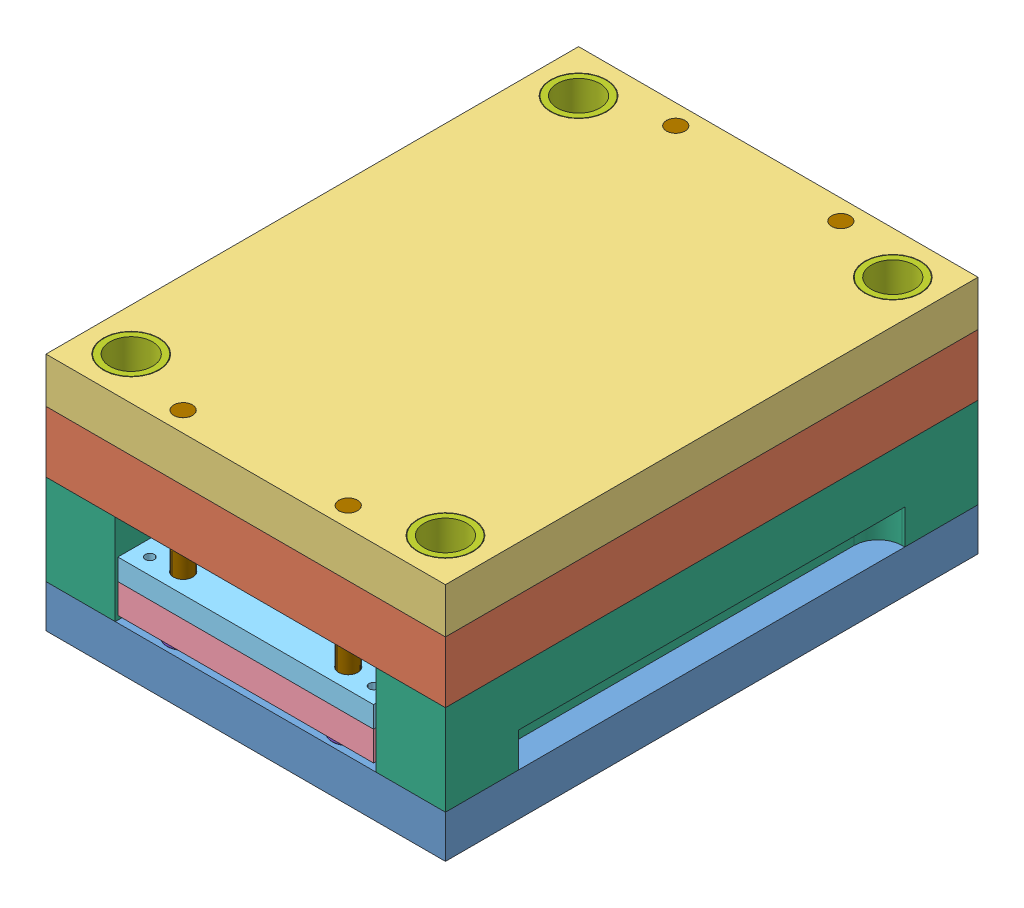
SolidWorks assembly Porta molde 300x400 Parte Inferior, configuration Valor predeterminado. Lengths in mm.
Overall size (300 180 401.07).
34 component instances, 12 part files, 38 mates.
Components (placement in the parent):
- Placa base inferior-1: Placa base inferior [Valor predeterminado] at (12.8367 -5.899 0) size (300 32 400)
- Placa suporte-1: Placa suporte [Valor predeterminado] at (12.8367 94.101 0) size (300 46 400)
- Placa cavidade P2-1: Placa cavidade P2 [Valor predeterminado] at (12.8367 140.101 0) size (300 34 400)
- Placa extratora CPE-1: Placa extratora CPE [Valor predeterminado] at (12.8367 53.101 0) x (-1 0 0) z (0 0 1) size (192 22 400)
- Placa extratora PE-1: Placa extratora PE [Valor predeterminado] at (12.8367 53.101 0) size (192 16 400)
- Espaçador-3: Espaçador [Valor predeterminado] at (110.8367 94.101 200) x (1 0 0) z (0 0 -1) size (52 68 400)
- Espaçador-4: Espaçador [Valor predeterminado] at (-85.1633 94.101 -200) x (-1 0 0) z (0 0 1) size (52 68 400)
- Socket Head Cap Screw_ISO-3: Socket Head Cap Screw_ISO [ISO 4762 M6 x 25 --- 25N] at (30.3367 349.101 -30.3109) x (0 -1 0) z (0.216767 0 0.976223) (suppressed, hidden)
- Socket Head Cap Screw_ISO-6: Socket Head Cap Screw_ISO [ISO 4762 M16 x 30 --- 30N] at (130.8367 340.101 -119) x (0 -1 0) z (0 0 1) (suppressed, hidden)
- Bucha-1: Bucha [B16] at (130.8367 140.101 168) x (0 1 0) z (0 0 1) size (34 48 48)
- Socket Head Cap Screw_ISO-10: Socket Head Cap Screw_ISO [ISO 4762 M16 x 150 --- 44N] at (130.8367 -5.899 -119) x (0 1 0) z (0 0 1) (suppressed, hidden)
- Bucha-2: Bucha [B16] at (130.8367 140.101 -168) x (0 1 0) z (0 0 1) size (34 48 48)
- Bucha-3: Bucha [B16] at (-105.1633 140.101 168) x (0 1 0) z (0 0 1) size (34 48 48)
- Bucha-4: Bucha [B16] at (-105.1633 140.101 -168) x (0 1 0) z (0 0 1) size (34 48 48)
- Socket Head Cap Screw_ISO-14: Socket Head Cap Screw_ISO [ISO 4762 M8 x 25 --- 25N] at (-71.1633 31.101 188) x (0 1 0) z (0 0 1) (suppressed, hidden)
- Socket Head Cap Screw_ISO-15: Socket Head Cap Screw_ISO [ISO 4762 M8 x 25 --- 25N] at (-71.1633 31.101 -188) x (0 1 0) z (0 0 1) (suppressed, hidden)
- Socket Head Cap Screw_ISO-16: Socket Head Cap Screw_ISO [ISO 4762 M8 x 25 --- 25N] at (96.8367 31.101 188) x (0 1 0) z (0 0 1) (suppressed, hidden)
- Socket Head Cap Screw_ISO-17: Socket Head Cap Screw_ISO [ISO 4762 M8 x 25 --- 25N] at (96.8367 31.101 -188) x (0 1 0) z (0 0 1) (suppressed, hidden)
- PA 02-1: PA 02 [Valor predeterminado] at (-49.1633 11.101 185) size (24 20 24)
- PA 02-2: PA 02 [Valor predeterminado] at (-49.1633 11.101 -185) size (24 20 24)
- PA 02-3: PA 02 [Valor predeterminado] at (74.8367 11.101 185) size (24 20 24)
- PA 02-4: PA 02 [Valor predeterminado] at (74.8367 11.101 -185) size (24 20 24)
- Extrator-1: Extrator [Valor predeterminado] at (-49.1633 53.101 185) x (0.670266 0 -0.742121) z (0.742121 0 0.670266) size (22 121 22)
- Extrator-2: Extrator [Valor predeterminado] at (-49.1633 53.101 -185) x (0.670266 0 -0.742121) z (0.742121 0 0.670266) size (22 121 22)
- Extrator-3: Extrator [Valor predeterminado] at (74.8367 53.101 185) x (0.670266 0 -0.742121) z (0.742121 0 0.670266) size (22 121 22)
- Extrator-4: Extrator [Valor predeterminado] at (74.8367 53.101 -185) x (0.670266 0 -0.742121) z (0.742121 0 0.670266) size (22 121 22)
- Bucha 2-1: Bucha 2 [Valor predeterminado] at (83.8367 31.101 153) x (0 1 0) z (0 0 1) size (38 38.1 38.1)
- Pino 2-1: Pino 2 [Valor predeterminado] at (83.8367 -5.899 153) x (0 1 0) z (0 0 1) size (102 38 38)
- Bucha 2-2: Bucha 2 [Valor predeterminado] at (83.8367 31.101 -153) x (0 1 0) z (0 0 1) size (38 38.1 38.1)
- Bucha 2-3: Bucha 2 [Valor predeterminado] at (-58.1633 31.101 153) x (0 1 0) z (0 0 1) size (38 38.1 38.1)
- Bucha 2-4: Bucha 2 [Valor predeterminado] at (-58.1633 31.101 -153) x (0 1 0) z (0 0 1) size (38 38.1 38.1)
- Pino 2-2: Pino 2 [Valor predeterminado] at (83.8367 -5.899 -153) x (0 1 0) z (0 0 1) size (102 38 38)
- Pino 2-3: Pino 2 [Valor predeterminado] at (-58.1633 -5.899 153) x (0 1 0) z (0 0 1) size (102 38 38)
- Pino 2-4: Pino 2 [Valor predeterminado] at (-58.1633 -5.899 -153) x (0 1 0) z (0 0 1) size (102 38 38)
Mates (geometry in assembly coordinates):
- Coincidente11: coincident anti-aligned: plane of Placa suporte-1 through (-137.1633 140.101 200) normal (0 1 0); plane of Placa cavidade P2-1 through (-137.1633 140.101 200) normal (0 -1 0)
- Coincidente12: coincident aligned: plane of Placa suporte-1 through (-137.1633 140.101 200) normal (0 0 1); plane of Placa cavidade P2-1 through (-137.1633 174.101 200) normal (0 0 1)
- Coincidente13: coincident aligned: plane of Placa suporte-1 through (162.8367 140.101 -200) normal (1 0 0); plane of Placa cavidade P2-1 through (162.8367 174.101 -200) normal (1 0 0)
- Paralelo1: parallel anti-aligned: plane of Placa base inferior-1 through (-137.1633 26.101 200) normal (0 1 0); plane of Placa extratora CPE-1 through (108.8367 31.101 200) normal (0 -1 0)
- Coincidente21: coincident aligned: plane of Placa base inferior-1 through (-137.1633 26.101 200) normal (0 0 1); plane of Placa extratora CPE-1 through (108.8367 31.101 200) normal (0 0 1)
- Coincidente22: coincident anti-aligned: plane of Placa extratora CPE-1 through (108.8367 53.101 200) normal (0 1 0); plane of Placa extratora PE-1 through (-83.1633 53.101 200) normal (0 -1 0)
- Coincidente23: coincident aligned: plane of Placa extratora CPE-1 through (108.8367 31.101 -200) normal (1 0 0); plane of Placa extratora PE-1 through (108.8367 69.101 -200) normal (1 0 0)
- Coincidente24: coincident aligned: plane of Placa extratora CPE-1 through (108.8367 31.101 200) normal (0 0 1); plane of Placa extratora PE-1 through (-83.1633 69.101 200) normal (0 0 1)
- Coincidente28: coincident anti-aligned: plane of Placa base inferior-1 through (-137.1633 26.101 200) normal (0 1 0); plane of Espaçador-3 through (110.8367 26.101 -200) normal (0 -1 0)
- Coincidente29: coincident aligned: plane of Placa base inferior-1 through (-137.1633 26.101 200) normal (0 0 1); plane of Espaçador-3 through (110.8367 26.101 200) normal (0 0 1)
- Coincidente30: coincident aligned: plane of Placa base inferior-1 through (162.8367 26.101 -200) normal (1 0 0); plane of Espaçador-3 through (162.8367 94.101 -200) normal (1 0 0)
- Coincidente31: coincident anti-aligned: plane of Placa suporte-1 through (-137.1633 94.101 200) normal (0 -1 0); plane of Espaçador-3 through (110.8367 94.101 -200) normal (0 1 0)
- Coincidente32: coincident aligned: plane of Placa suporte-1 through (162.8367 140.101 -200) normal (1 0 0); plane of Espaçador-3 through (162.8367 94.101 -200) normal (1 0 0)
- Coincidente33: coincident aligned: plane of Placa suporte-1 through (-137.1633 140.101 200) normal (0 0 1); plane of Espaçador-3 through (110.8367 26.101 200) normal (0 0 1)
- Coincidente34: coincident aligned: plane of Placa base inferior-1 through (-137.1633 26.101 -200) normal (-1 0 0); plane of Espaçador-4 through (-137.1633 94.101 200) normal (-1 0 0)
- Coincidente35: coincident aligned: plane of Placa base inferior-1 through (-137.1633 26.101 200) normal (0 0 1); plane of Espaçador-4 through (-85.1633 26.101 200) normal (0 0 1)
- Coincidente36: coincident anti-aligned: plane of Placa suporte-1 through (-137.1633 94.101 200) normal (0 -1 0); plane of Espaçador-4 through (-85.1633 94.101 200) normal (0 1 0)
- Coincidente40: coincident anti-aligned: plane of Placa cavidade P2-1 through (151.8367 148.101 168) normal (0 -1 0); plane of Bucha-1 through (106.8367 148.101 168) normal (0 1 0)
- Concêntrico5: concentric aligned: cylinder of Placa cavidade P2-1 through (130.8367 140.101 168) axis (0 -1 0) radius 21; cylinder of Bucha-1 through (130.8367 1.1757 168) axis (0 -1 0) radius 21
- Coincidente43: coincident anti-aligned: plane of Placa base inferior-1; plane of Socket Head Cap Screw_ISO-10
- Concêntrico8: concentric aligned: cylinder of Placa base inferior-1; cylinder of Socket Head Cap Screw_ISO-10
- Coincidente45: coincident anti-aligned: plane of Placa extratora CPE-1; plane of Socket Head Cap Screw_ISO-14
- Concêntrico10: concentric aligned: cylinder of Placa extratora CPE-1; cylinder of Socket Head Cap Screw_ISO-14
- Concêntrico11: concentric anti-aligned: cylinder of Placa base inferior-1 through (-49.1633 26.101 185) axis (0 1 0) radius 7; cylinder of PA 02-1 through (-49.1633 11.101 185) axis (0 -1 0) radius 7
- Coincidente46: coincident anti-aligned: plane of Placa base inferior-1 through (-137.1633 26.101 200) normal (0 1 0); plane of PA 02-1 through (-37.1633 26.101 185) normal (0 -1 0)
- Paralelo2: parallel anti-aligned: plane of Placa extratora CPE-1 through (108.8367 31.101 200) normal (0 -1 0); plane of PA 02-1 through (-49.1633 31.101 185) normal (0 1 0)
- Concêntrico12: concentric aligned: cylinder of Placa extratora PE-1 through (-49.1633 53.101 185) axis (0 -1 0) radius 7.25; cylinder of Extrator-1 through (-49.1633 53.101 185) axis (0 -1 0) radius 7
- Coincidente48: coincident anti-aligned: plane of Placa extratora CPE-1 through (108.8367 53.101 200) normal (0 1 0); plane of Extrator-1 through (-41.7904 53.101 176.8367) normal (0 -1 0)
- Concêntrico13: concentric aligned: cylinder of Placa cavidade P2-1 through (74.8367 140.101 185) axis (0 -1 0) radius 7; cylinder of Extrator-3 through (74.8367 53.101 185) axis (0 -1 0) radius 7
- Concêntrico14: concentric aligned: cylinder of Placa extratora PE-1 through (74.8367 53.101 185) axis (0 -1 0) radius 7.25; cylinder of Extrator-3 through (74.8367 53.101 185) axis (0 -1 0) radius 7
- Coincidente49: coincident anti-aligned: plane of Placa extratora CPE-1 through (67.8367 46.101 153) normal (0 1 0); plane of Bucha 2-1 through (67.8367 46.101 153) normal (0 -1 0)
- Concêntrico15: concentric anti-aligned: cylinder of Placa extratora CPE-1 through (83.8367 53.101 153) axis (0 1 0) radius 16; cylinder of Bucha 2-1 through (83.8367 -59.5152 153) axis (0 -1 0) radius 16
- Coincidente50: coincident aligned: plane of Placa base inferior-1 through (-137.1633 -5.899 200) normal (0 -1 0); plane of Pino 2-1 through (83.8367 -5.899 153) normal (0 -1 0)
- Concêntrico16: concentric aligned: cylinder of Placa base inferior-1 through (83.8367 -5.899 153) axis (0 -1 0) radius 16; cylinder of Pino 2-1 through (83.8367 -159.3058 153) axis (0 -1 0) radius 16
- LimitDistance1: limit distance = 0 mm aligned: plane of Placa cavidade P2-1 through (-137.1633 174.101 200) normal (0 1 0); plane of Extrator-1 through (-49.1633 174.101 185) normal (0 1 0)
- LocalLPattern3: unknown: line of Placa extratora CPE-1 through (108.8367 31.101 200) axis (-1 0 0); line of Placa extratora CPE-1 through (108.8367 31.101 -200) axis (0 0 1)
- LocalLPattern4: unknown: line of Placa base inferior-1 through (-137.1633 26.101 200) axis (1 0 0); line of Placa base inferior-1 through (162.8367 26.101 200) axis (0 0 -1)
- LocalLPattern5: unknown: line of Placa extratora PE-1 through (-83.1633 69.101 200) axis (1 0 0)
